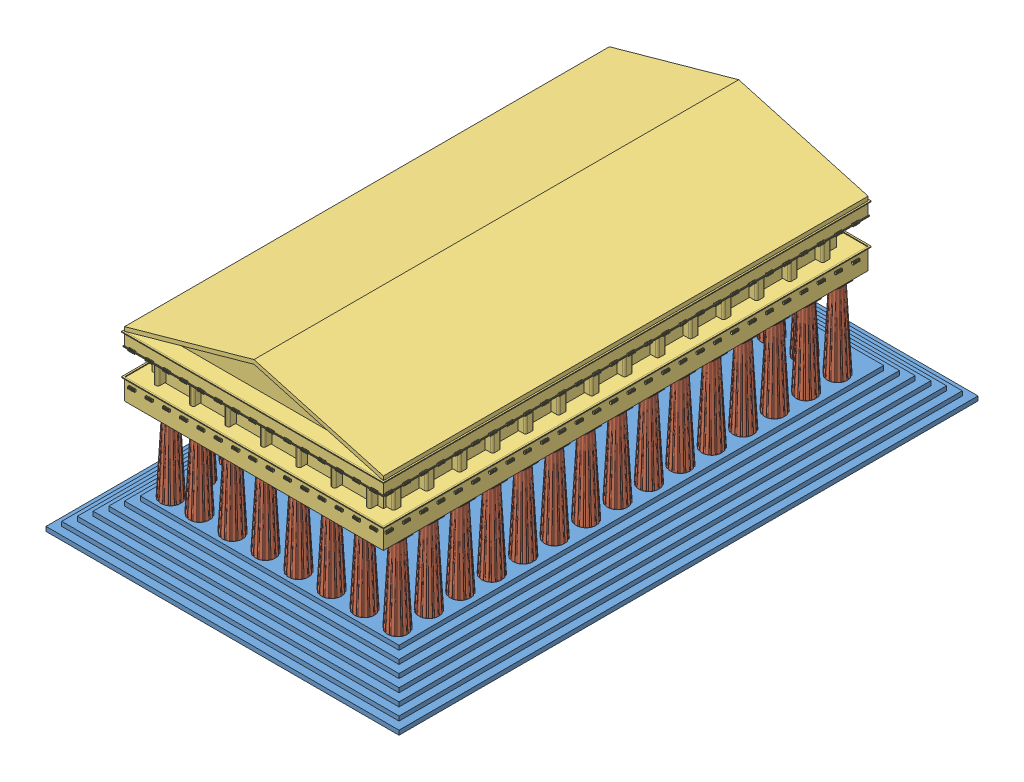
SolidWorks assembly assem_final, configuration Default. Lengths in mm.
Overall size (44.94 27.46 73.7).
45 component instances, 3 part files, 4 mates.
Components (placement in the parent):
- parthenon_base-1: parthenon_base [Default] at (-11.0896 3.1982 28.3251) size (44.94 3.92 73.7)
- parthenon_pillar-2: parthenon_pillar [Default] at (9.9021 3.2982 -4.2756) x (1 0 0) z (0 1 0) size (2.62 2.64 10.72)
- parthenon_pillar-3: parthenon_pillar [Default] at (9.9021 3.2982 -8.2756) x (1 0 0) z (0 1 0) size (2.62 2.64 10.72)
- parthenon_pillar-4: parthenon_pillar [Default] at (9.9021 3.2982 -12.2756) x (1 0 0) z (0 1 0) size (2.62 2.64 10.72)
- parthenon_pillar-5: parthenon_pillar [Default] at (9.9021 3.2982 -16.2756) x (1 0 0) z (0 1 0) size (2.62 2.64 10.72)
- parthenon_pillar-6: parthenon_pillar [Default] at (9.9021 3.2982 -20.2756) x (1 0 0) z (0 1 0) size (2.62 2.64 10.72)
- parthenon_pillar-7: parthenon_pillar [Default] at (9.9021 3.2982 -24.2756) x (1 0 0) z (0 1 0) size (2.62 2.64 10.72)
- parthenon_pillar-8: parthenon_pillar [Default] at (9.9021 3.2982 -28.2756) x (1 0 0) z (0 1 0) size (2.62 2.64 10.72)
- parthenon_pillar-9: parthenon_pillar [Default] at (9.9021 3.2982 -32.2756) x (1 0 0) z (0 1 0) size (2.62 2.64 10.72)
- parthenon_pillar-10: parthenon_pillar [Default] at (9.9021 3.2982 -36.2756) x (1 0 0) z (0 1 0) size (2.62 2.64 10.72)
- parthenon_pillar-11: parthenon_pillar [Default] at (9.9021 3.2982 -40.2756) x (1 0 0) z (0 1 0) size (2.62 2.64 10.72)
- parthenon_pillar-12: parthenon_pillar [Default] at (9.9021 3.2982 -44.2756) x (1 0 0) z (0 1 0) size (2.62 2.64 10.72)
- parthenon_pillar-13: parthenon_pillar [Default] at (9.9021 3.2982 -48.2756) x (1 0 0) z (0 1 0) size (2.62 2.64 10.72)
- parthenon_pillar-14: parthenon_pillar [Default] at (9.9021 3.2982 -52.2756) x (1 0 0) z (0 1 0) size (2.62 2.64 10.72)
- parthenon_pillar-15: parthenon_pillar [Default] at (9.9021 3.2982 -56.2756) x (1 0 0) z (0 1 0) size (2.62 2.64 10.72)
- parthenon_pillar-16: parthenon_pillar [Default] at (9.9021 3.2982 -60.2756) x (1 0 0) z (0 1 0) size (2.62 2.64 10.72)
- parthenon_pillar-17: parthenon_pillar [Default] at (-18.9519 3.2982 -4.2756) x (1 0 0) z (0 1 0) size (2.62 2.64 10.72)
- parthenon_pillar-18: parthenon_pillar [Default] at (-18.9519 3.2982 -8.2756) x (1 0 0) z (0 1 0) size (2.62 2.64 10.72)
- parthenon_pillar-19: parthenon_pillar [Default] at (-18.9519 3.2982 -12.2756) x (1 0 0) z (0 1 0) size (2.62 2.64 10.72)
- parthenon_pillar-20: parthenon_pillar [Default] at (-18.9519 3.2982 -16.2756) x (1 0 0) z (0 1 0) size (2.62 2.64 10.72)
- parthenon_pillar-21: parthenon_pillar [Default] at (-18.9519 3.2982 -20.2756) x (1 0 0) z (0 1 0) size (2.62 2.64 10.72)
- parthenon_pillar-22: parthenon_pillar [Default] at (-18.9519 3.2982 -24.2756) x (1 0 0) z (0 1 0) size (2.62 2.64 10.72)
- parthenon_pillar-23: parthenon_pillar [Default] at (-18.9519 3.2982 -28.2756) x (1 0 0) z (0 1 0) size (2.62 2.64 10.72)
- parthenon_pillar-24: parthenon_pillar [Default] at (-18.9519 3.2982 -32.2756) x (1 0 0) z (0 1 0) size (2.62 2.64 10.72)
- parthenon_pillar-25: parthenon_pillar [Default] at (-18.9519 3.2982 -36.2756) x (1 0 0) z (0 1 0) size (2.62 2.64 10.72)
- parthenon_pillar-26: parthenon_pillar [Default] at (-18.9519 3.2982 -40.2756) x (1 0 0) z (0 1 0) size (2.62 2.64 10.72)
- parthenon_pillar-27: parthenon_pillar [Default] at (-18.9519 3.2982 -44.2756) x (1 0 0) z (0 1 0) size (2.62 2.64 10.72)
- parthenon_pillar-28: parthenon_pillar [Default] at (-18.9519 3.2982 -48.2756) x (1 0 0) z (0 1 0) size (2.62 2.64 10.72)
- parthenon_pillar-29: parthenon_pillar [Default] at (-18.9519 3.2982 -52.2756) x (1 0 0) z (0 1 0) size (2.62 2.64 10.72)
- parthenon_pillar-30: parthenon_pillar [Default] at (-18.9519 3.2982 -56.2756) x (1 0 0) z (0 1 0) size (2.62 2.64 10.72)
- parthenon_pillar-31: parthenon_pillar [Default] at (-18.9519 3.2982 -60.2756) x (1 0 0) z (0 1 0) size (2.62 2.64 10.72)
- parthenon_pillar-32: parthenon_pillar [Default] at (5.7021 3.2982 -4.2756) x (1 0 0) z (0 1 0) size (2.62 2.64 10.72)
- parthenon_pillar-33: parthenon_pillar [Default] at (1.5021 3.2982 -4.2756) x (1 0 0) z (0 1 0) size (2.62 2.64 10.72)
- parthenon_pillar-34: parthenon_pillar [Default] at (-2.6979 3.2982 -4.2756) x (1 0 0) z (0 1 0) size (2.62 2.64 10.72)
- parthenon_pillar-35: parthenon_pillar [Default] at (-6.8979 3.2982 -4.2756) x (1 0 0) z (0 1 0) size (2.62 2.64 10.72)
- parthenon_pillar-36: parthenon_pillar [Default] at (-11.0979 3.2982 -4.2756) x (1 0 0) z (0 1 0) size (2.62 2.64 10.72)
- parthenon_pillar-37: parthenon_pillar [Default] at (-15.2979 3.2982 -4.2756) x (1 0 0) z (0 1 0) size (2.62 2.64 10.72)
- parthenon_pillar-38: parthenon_pillar [Default] at (9.9021 3.2982 -60.2756) x (1 0 0) z (0 1 0) size (2.62 2.64 10.72)
- parthenon_pillar-39: parthenon_pillar [Default] at (5.7021 3.2982 -60.2756) x (1 0 0) z (0 1 0) size (2.62 2.64 10.72)
- parthenon_pillar-40: parthenon_pillar [Default] at (1.5021 3.2982 -60.2756) x (1 0 0) z (0 1 0) size (2.62 2.64 10.72)
- parthenon_pillar-41: parthenon_pillar [Default] at (-2.6979 3.2982 -60.2756) x (1 0 0) z (0 1 0) size (2.62 2.64 10.72)
- parthenon_pillar-42: parthenon_pillar [Default] at (-6.8979 3.2982 -60.2756) x (1 0 0) z (0 1 0) size (2.62 2.64 10.72)
- parthenon_pillar-43: parthenon_pillar [Default] at (-11.0979 3.2982 -60.2756) x (1 0 0) z (0 1 0) size (2.62 2.64 10.72)
- parthenon_pillar-44: parthenon_pillar [Default] at (-15.2979 3.2982 -60.2756) x (1 0 0) z (0 1 0) size (2.62 2.64 10.72)
- pillar_above-1: pillar_above [Default] at (62.4863 13.9232 -9.1936) size (33.34 12.82 62.1)
Mates (geometry in assembly coordinates):
- Coincident2: coincident anti-aligned: plane of parthenon_base-1 through (-11.0896 3.1982 28.3251) normal (0 1 0); plane of parthenon_pillar-2 through (17.7554 3.1982 26.6148) normal (0 -1 0)
- Distance1: distance = 0 mm anti-aligned: plane of pillar_above-1 through (62.4863 13.9232 -9.1936) normal (0 -1 0); plane of parthenon_pillar-2 through (9.9021 13.9232 -4.2756) normal (0 1 0)
- Parallel1: parallel aligned: line of parthenon_pillar-2 through (16.768 13.9232 27.6023) axis (1 0 0); line of pillar_above-1 through (-13.9935 13.9232 29.1023) axis (1 0 0)
- Distance2: distance = 2 mm aligned: plane of pillar_above-1 through (18.9465 15.8232 29.6023) normal (0 0 1); plane of parthenon_pillar-35 through (-0.032 13.9232 27.6023) normal (0 0 1)
